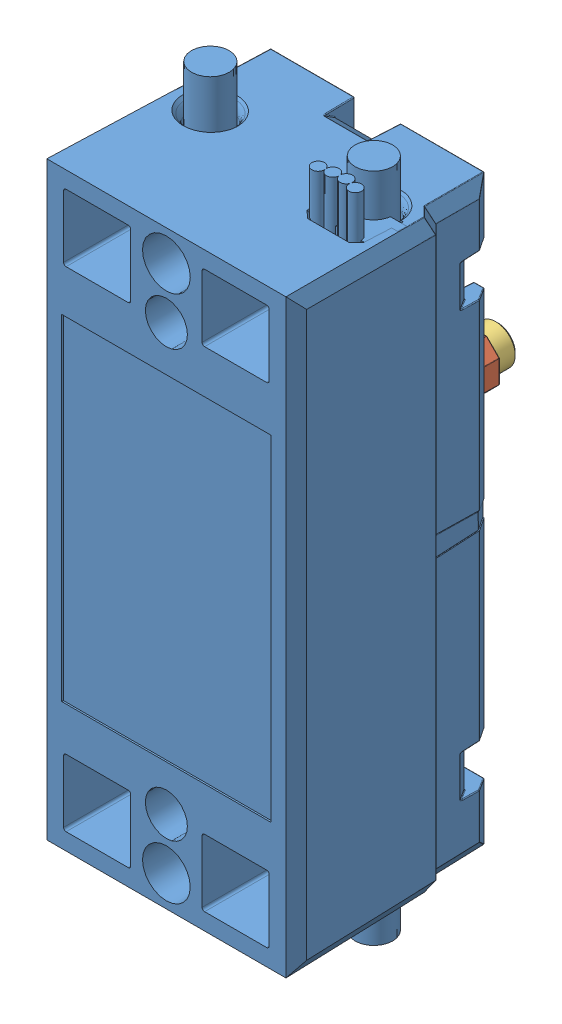
SolidWorks assembly Talon SRX, configuration Default. Lengths in mm.
Overall size (30.47 80 30.19).
4 component instances, 3 part files, 0 mates.
Components (placement in the parent):
- Copy of 217-8080-baseRev4_no wires^Talon SRX-1: Copy of 217-8080-baseRev4_no wires^Talon SRX [Default] at origin size (30.47 80 25.21) (virtual)
- Copy of 217-8080-002 Rev1^Talon SRX-1: Copy of 217-8080-002 Rev1^Talon SRX [Default] at (0 13.05 -9.65) x (1 0 0) z (0 -1 0) size (25.15 2.91 7.5) (virtual)
- Copy of 217-8080-005 Rev1_91251A105^Talon SRX-1: Copy of 217-8080-005 Rev1_91251A105^Talon SRX [Default] at (-9.525 13.05 -5.8875) size (4.65 4.65 7.74) (virtual)
- Copy of 217-8080-005 Rev1_91251A105^Talon SRX-2: Copy of 217-8080-005 Rev1_91251A105^Talon SRX [Default] at (9.525 13.05 -5.8875) size (4.65 4.65 7.74) (virtual)
